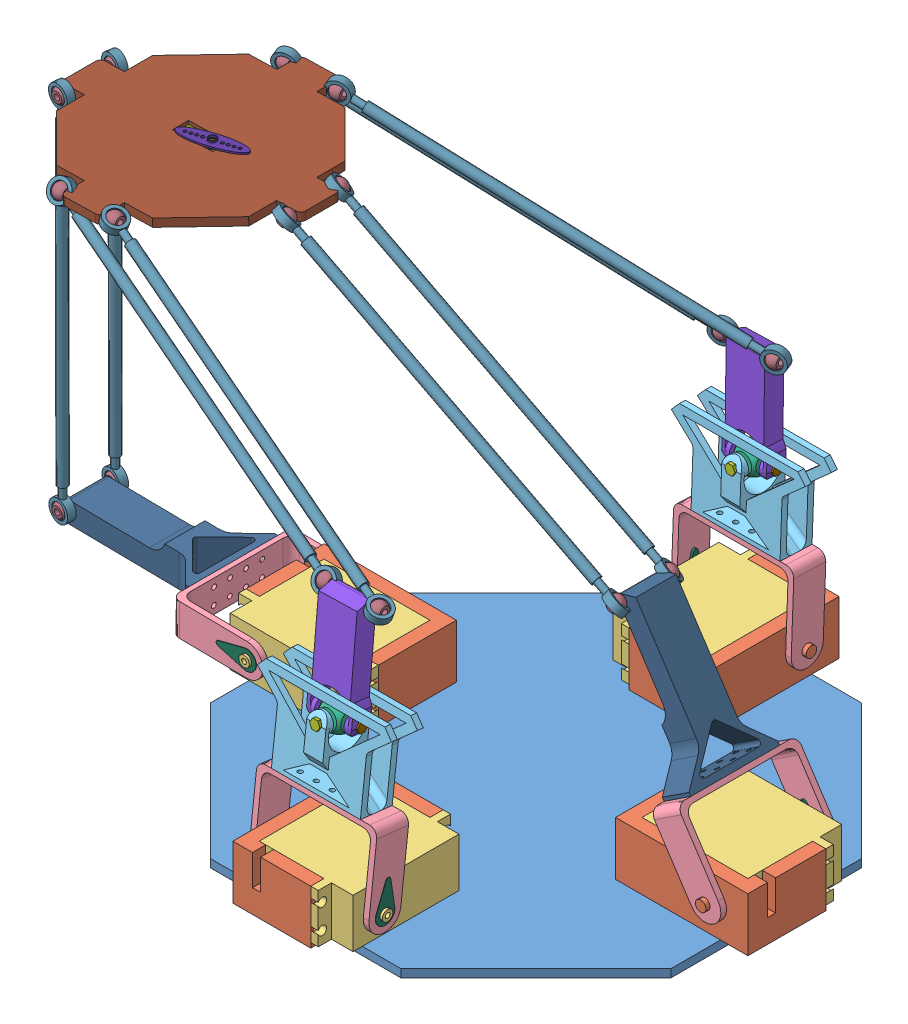
SolidWorks assembly asm(backup), configuration 기본. Lengths in mm.
Overall size (442.11 264.41 321.27).
68 component instances, 17 part files, 159 mates.
Components (placement in the parent):
- delta_base_-1: delta_base_ [기본] at (16.2815 -22.3997 221) size (287.2 5 287.2)
- servobracket1_-1: servobracket1_ [기본] at (8418.954 -14.3997 21660.4366) x (0 0 -1) z (0 1 0) size (82.55 54.75 33.48)
- servobracket1_-2: servobracket1_ [기본] at (-21423.155 -14.3997 8623.6725) x (1 0 0) z (0 1 0) size (82.55 54.75 33.48)
- servobracket1_-3: servobracket1_ [기본] at (-8386.3909 -14.3997 -21218.4366) x (0 0 1) z (0 1 0) size (82.55 54.75 33.48)
- servobracket1_-4: servobracket1_ [기본] at (21455.7181 -14.3997 -8181.6725) x (-1 0 0) z (0 1 0) size (82.55 54.75 33.48)
- servo_drive_HV2060MG-1: servo_drive_HV2060MG [기본] at (-103.0792 0.8403 200.815) x (-1 0 0) z (0 0 1) size (82.55 30.48 64.98)
- servo_drive_HV2060MG-2: servo_drive_HV2060MG [기본] at (36.4665 0.8403 101.6393) x (0 0 -1) z (-1 0 0) size (82.55 30.48 64.98)
- servo_drive_HV2060MG-3: servo_drive_HV2060MG [기본] at (135.6423 0.8403 241.185) x (1 0 0) z (0 0 -1) size (82.55 30.48 64.98)
- servo_drive_HV2060MG-4: servo_drive_HV2060MG [기본] at (-3.9035 0.8403 340.3607) x (0 0 1) z (1 0 0) size (82.55 30.48 64.98)
- servobracket2_-1: servobracket2_ [기본] at (20.8415 47.532 352.9063) x (1 0 0) z (0 -0.114353 -0.99344) size (75 57 20)
- servobracket2_-2: servobracket2_ [기본] at (11.7215 47.8073 81.9563) x (-1 0 0) z (0 0.037506 0.999296) size (75 57 20)
- univ_link1-1: univ_link1 [기본] at (14.8415 69.6769 350.3572) x (0 0.114353 0.99344) z (1 0 0) size (28.84 52.05 83.6)
- univ_link1-2: univ_link1 [기본] at (5.7215 70.0827 81.1203) x (0 0.037506 0.999296) z (1 0 0) size (28.84 52.05 83.6)
- ball-1: ball [기본] at (20.8415 84.5835 348.6413) x (-0.999736 -0.022829 0.002628) z (0 -0.114353 -0.99344) size (24 24 18)
- ball-2: ball [기본] at (11.7215 85.0771 80.5575) x (0.999693 0.024771 -0.00093) z (0 0.037506 0.999296) size (24 24 18)
- univ_bolt_-1: univ_bolt_ [기본] at (20.8415 82.8682 333.7399) x (1 0 0) z (0 -0.99344 0.114353) size (6.46 12 5.59)
- univ_bolt_-2: univ_bolt_ [기본] at (11.7215 85.6397 95.5471) x (0.5 -0.865416 0.032481) z (0.866025 0.499648 -0.018753) size (6.46 12 5.59)
- univ_bolt_-3: univ_bolt_ [기본] at (20.8415 86.2988 363.5431) x (1 0 0) z (0 0.99344 -0.114353) size (6.46 12 5.59)
- univ_bolt_-4: univ_bolt_ [기본] at (11.7215 84.5145 65.5682) x (0.5 0.865416 -0.032481) z (0.866025 -0.499648 0.018753) size (6.46 12 5.59)
- univ_link2-3: univ_link2 [기본] at (11.3614 100.2778 85.9912) x (-0.999693 -0.024771 0.00093) z (0 -0.037506 -0.999296) size (28.56 68.77 12)
- univ_bolt2_-1: univ_bolt2_ [기본] at (26.7282 85.449 80.5435) x (0 0.037506 0.999296) z (0.024788 -0.998989 0.037495) size (6.46 12 5.59)
- univ_bolt2_-2: univ_bolt2_ [기본] at (-3.2626 84.7059 80.5714) x (0 -0.037506 -0.999296) z (0.024788 -0.998989 0.037495) size (6.46 12 5.59)
- univ_link2-4: univ_link2 [기본] at (20.5081 98.7858 340.9669) x (0.999736 0.022829 -0.002628) z (0 0.114353 0.99344) size (28.56 68.77 12)
- univ_bolt2_-3: univ_bolt2_ [기본] at (5.8568 84.2413 348.6807) x (0 -0.114353 -0.99344) z (0.02298 -0.993178 0.114323) size (6.46 12 5.59)
- univ_bolt2_-4: univ_bolt2_ [기본] at (35.8489 84.9262 348.6019) x (0 0.114353 0.99344) z (0.02298 -0.993178 0.114323) size (6.46 12 5.59)
- servobracket2_-3: servobracket2_ [기본] at (-167.995 1.4804 225.56) x (0 0 1) z (0.013619 0.999907 0) size (75 57 20)
- servobracket2_-4: servobracket2_ [기본] at (127.7255 40.1017 216.44) x (0 0 -1) z (-0.835348 -0.549722 0) size (75 57 20)
- link1_-1: link1_ [기본] at (119.372 34.6045 244.19) x (0 0 -1) z (0.549722 -0.835348 0) size (55.5 20 93)
- link1_-2: link1_ [기본] at (-167.8588 11.4795 197.81) x (0 0 1) z (0.999907 -0.013619 0) size (55.5 20 93)
- delta_end_-1: delta_end_ [기본] at (-185.4361 233.7506 228.4598) x (-0.999712 -0.023985 0) z (0 0 1) size (150 5 150)
- link_bridge_-1: link_bridge_ [기본] at (78.2493 115.2848 216.4377) x (-1 0 0) z (0 1 0) size (4.5 28.5 4.5)
- bearing-1: bearing [기본] at (78.2493 115.2848 200.0127) x (0 1 0) z (1 0 0) size (9.35 6.85 9.35)
- link_bridge_-2: link_bridge_ [기본] at (-115.3963 232.9302 228.4598) x (0.013819 0.999905 0) z (0.999905 -0.013819 0) size (4.5 28.5 4.5)
- bearing-2: bearing [기본] at (-115.3963 232.9302 212.0348) x (0.999983 -0.005841 0) z (-0.005841 -0.999983 0) size (9.35 6.85 9.35)
- bearing-3: bearing [기본] at (78.2493 115.2848 232.8627) x (1 0 0) z (0 -1 0) size (9.35 6.85 9.35)
- bearing-4: bearing [기본] at (-115.3963 232.9302 244.8848) x (0 -1 0) z (1 0 0) size (9.35 6.85 9.35)
- rod-1: rod [기본] at (78.2493 115.2848 232.8627) x (-0.371477 -0.533829 -0.759626) z (-0.85344 0.51849 0.052984) size (13.45 6 240.35)
- rod-2: rod [기본] at (-115.3963 232.9302 212.0348) x (0.350098 0.495 0.79524) z (0.85344 -0.51849 -0.052984) size (13.45 6 240.35)
- link_bridge_-3: link_bridge_ [기본] at (-255.356 229.5724 228.4598) x (0.064888 0.997893 0) z (0.997893 -0.064888 0) size (4.5 28.5 4.5)
- bearing-5: bearing [기본] at (-255.356 229.5724 244.8848) x (-0.114329 0.993443 0) z (-0.993443 -0.114329 0) size (9.35 6.85 9.35)
- bearing-6: bearing [기본] at (-255.356 229.5724 212.0348) x (1 0 0) z (0 -1 0) size (9.35 6.85 9.35)
- link_bridge_-4: link_bridge_ [기본] at (-257.9888 2.7062 225.5623) x (1 0 0) z (0 -1 0) size (4.5 28.5 4.5)
- bearing-7: bearing [기본] at (-257.9888 2.7062 209.1373) x (1 0 0) z (0 -1 0) size (9.35 6.85 9.35)
- bearing-8: bearing [기본] at (-257.9888 2.7062 241.9873) x (-1 0 0) z (0 -1 0) size (9.35 6.85 9.35)
- rod-3: rod [기본] at (-255.356 229.5724 212.0348) x (0.986689 -0.01352 0.162053) z (-0.011603 -0.999851 -0.01277) size (13.45 6 240.35)
- rod-4: rod [기본] at (-257.9888 2.7062 241.9873) x (-0.992561 0.013065 -0.121049) z (0.011603 0.999851 0.01277) size (13.45 6 240.35)
- link_bridge_-5: link_bridge_ [기본] at (-185.3762 231.2513 158.4598) x (-0.023985 0.999712 0) z (0 0 1) size (4.5 28.5 4.5)
- link_bridge_-6: link_bridge_ [기본] at (9.7461 144.8824 81.3149) x (-0.024303 0.986812 0.160038) z (-0.004882 0.159966 -0.98711) size (4.5 28.5 4.5)
- bearing-9: bearing [기본] at (-201.7964 230.8574 158.4598) x (0.000254 -0.010595 -0.999944) z (0.023983 -0.999656 0.010598) size (9.35 6.85 9.35)
- bearing-10: bearing [기본] at (-168.9559 231.6453 158.4598) x (-0.020319 0.846909 0.531349) z (0.012744 -0.531196 0.847153) size (9.35 6.85 9.35)
- bearing-11: bearing [기본] at (-6.6739 144.4756 81.3302) x (0.024303 -0.986812 -0.160038) z (0.004882 -0.159966 0.98711) size (9.35 6.85 9.35)
- bearing-12: bearing [기본] at (26.1661 145.2893 81.2997) x (-0.024303 0.986812 0.160038) z (0.004882 -0.159966 0.98711) size (9.35 6.85 9.35)
- rod-5: rod [기본] at (-201.7964 230.8574 158.4598) x (0.388785 0.920131 -0.046957) z (0.85995 -0.380704 -0.339928) size (13.45 6 240.35)
- rod-6: rod [기본] at (26.1661 145.2893 81.2997) x (-0.367193 -0.924119 0.1057) z (-0.859947 0.38059 0.340062) size (13.45 6 240.35)
- link_bridge_-8: link_bridge_ [기본] at (19.9847 143.6099 338.8271) x (-0.022739 0.999274 0.030581) z (0.003324 -0.030514 0.999529) size (4.5 28.5 4.5)
- bearing-13: bearing [기본] at (36.4053 143.9849 338.7839) x (-0.021503 0.969673 0.243459) z (0.008106 -0.243338 0.969908) size (9.35 6.85 9.35)
- bearing-15: bearing [기본] at (3.564 143.2349 338.8702) x (0.022738 -0.999273 -0.030614) z (0.003325 -0.030546 0.999528) size (9.35 6.85 9.35)
- rod-8: rod [기본] at (36.4053 143.9849 338.7839) x (-0.186319 0.015405 0.982368) z (-0.905074 0.386339 -0.177718) size (13.45 6 240.35)
- rod-9: rod [기본] at (3.564 143.2349 338.8702) x (-0.419444 -0.741594 0.523551) z (-0.90507 0.386172 -0.178098) size (13.45 6 240.35)
- servobracket3_-2: servobracket3_ [기본] at (153.5748 0.8403 177.7076) x (-0.835348 -0.549722 0) z (-0.549722 0.835348 0) size (12 5 24.89)
- servobracket3_-3: servobracket3_ [기본] at (54.5739 0.8403 358.2932) x (0 0.114353 0.99344) z (0 0.99344 -0.114353) size (12 5 24.89)
- servobracket3_-4: servobracket3_ [기본] at (-22.0109 0.8403 83.7068) x (0 -0.037506 -0.999296) z (0 0.999296 -0.037506) size (12 5 24.89)
- servobracket3_-5: servobracket3_ [기본] at (-121.0117 0.8403 259.2924) x (-0.013619 -0.999907 0) z (-0.999907 0.013619 0) size (12 5 24.89)
- link_bridge_-9: link_bridge_ [기본] at (-185.3762 231.2513 298.4598) x (-0.023985 0.999712 0) z (0 0 -1) size (4.5 28.5 4.5)
- bearing-17: bearing [기본] at (-168.9559 231.6453 298.4598) x (-0.023288 0.970695 0.239183) z (-0.005737 0.239114 -0.970974) size (9.35 6.85 9.35)
- bearing-18: bearing [기본] at (-201.7964 230.8574 298.4598) x (-0.021793 0.908344 0.417655) z (0.010017 -0.417535 0.908606) size (9.35 6.85 9.35)
- motor-1: motor [기본] at (-185.0284 216.7555 228.4598) x (-0.999712 -0.023985 0) z (-0.023985 0.999712 0) size (32 10 18)
- motor_connect-1: motor_connect [기본] at (-177.9743 235.4301 228.4598) x (0.965622 0.023167 -0.258916) z (0.023985 -0.999712 0) size (38 10 5)
Mates (geometry in assembly coordinates):
- 동심1: concentric anti-aligned: cylinder of delta_base_-1 through (11.2815 -17.3997 82.46) axis (0 -1 0) radius 1.5; cylinder of servobracket1_-1 through (11.2815 -17.3997 82.46) axis (0 1 0) radius 1.5
- 동심2: concentric anti-aligned: cylinder of delta_base_-1 through (21.2815 -17.3997 92.46) axis (0 -1 0) radius 1.5; cylinder of servobracket1_-1 through (21.2815 -17.3997 92.46) axis (0 1 0) radius 1.5
- 일치1: coincident anti-aligned: plane of delta_base_-1 through (16.2815 -17.3997 221) normal (0 1 0); plane of servobracket1_-1 through (8418.954 -17.3997 21660.4366) normal (0 -1 0)
- 동심3: concentric anti-aligned: cylinder of delta_base_-1 through (154.8215 -17.3997 216) axis (0 -1 0) radius 1.5; cylinder of servobracket1_-2 through (154.8215 -17.3997 216) axis (0 1 0) radius 1.5
- 동심4: concentric anti-aligned: cylinder of delta_base_-1 through (144.8215 -17.3997 226) axis (0 -1 0) radius 1.5; cylinder of servobracket1_-2 through (144.8215 -17.3997 226) axis (0 1 0) radius 1.5
- 일치4: coincident anti-aligned: plane of delta_base_-1 through (16.2815 -17.3997 221) normal (0 1 0); plane of servobracket1_-2 through (-21423.155 -17.3997 8623.6725) normal (0 -1 0)
- 동심5: concentric anti-aligned: cylinder of delta_base_-1 through (21.2815 -17.3997 359.54) axis (0 -1 0) radius 1.5; cylinder of servobracket1_-3 through (21.2815 -17.3997 359.54) axis (0 1 0) radius 1.5
- 동심6: concentric anti-aligned: cylinder of delta_base_-1 through (11.2815 -17.3997 349.54) axis (0 -1 0) radius 1.5; cylinder of servobracket1_-3 through (11.2815 -17.3997 349.54) axis (0 1 0) radius 1.5
- 일치5: coincident anti-aligned: plane of delta_base_-1 through (16.2815 -17.3997 221) normal (0 1 0); plane of servobracket1_-3 through (-8386.3909 -17.3997 -21218.4366) normal (0 -1 0)
- 동심7: concentric anti-aligned: cylinder of delta_base_-1 through (-122.2585 -17.3997 226) axis (0 -1 0) radius 1.5; cylinder of servobracket1_-4 through (-122.2585 -17.3997 226) axis (0 1 0) radius 1.5
- 동심8: concentric anti-aligned: cylinder of delta_base_-1 through (-112.2585 -17.3997 216) axis (0 -1 0) radius 1.5; cylinder of servobracket1_-4 through (-112.2585 -17.3997 216) axis (0 1 0) radius 1.5
- 일치6: coincident anti-aligned: plane of delta_base_-1 through (16.2815 -17.3997 221) normal (0 1 0); plane of servobracket1_-4 through (21455.7181 -17.3997 -8181.6725) normal (0 -1 0)
- 일치7: coincident anti-aligned: plane of servobracket1_-4 through (-70.0592 16.0803 241.1804) normal (-1 0 0); plane of servo_drive_HV2060MG-1 through (-70.0592 16.0803 241.1904) normal (1 0 0)
- 일치8: coincident anti-aligned: plane of servobracket1_-4 through (-70.0592 16.0803 200.815) normal (0 0 1); plane of servo_drive_HV2060MG-1 through (-103.0792 0.8403 200.815) normal (0 0 -1)
- 일치9: coincident anti-aligned: plane of servobracket1_-4 through (21455.7181 -14.3997 -8181.6725) normal (0 1 0); plane of servo_drive_HV2060MG-1 through (-136.0992 -14.3997 241.1904) normal (0 -1 0)
- 일치10: coincident anti-aligned: plane of servobracket1_-1 through (-3.8989 16.0803 134.6593) normal (0 0 -1); plane of servo_drive_HV2060MG-2 through (-3.9089 16.0803 134.6593) normal (0 0 1)
- 일치11: coincident anti-aligned: plane of servobracket1_-1 through (36.4665 16.0803 134.6593) normal (-1 0 0); plane of servo_drive_HV2060MG-2 through (36.4665 0.8403 101.6393) normal (1 0 0)
- 일치12: coincident anti-aligned: plane of servobracket1_-1 through (8418.954 -14.3997 21660.4366) normal (0 1 0); plane of servo_drive_HV2060MG-2 through (-3.9089 -14.3997 68.6193) normal (0 -1 0)
- 일치13: coincident anti-aligned: plane of servobracket1_-2 through (102.6223 16.0803 200.8196) normal (1 0 0); plane of servo_drive_HV2060MG-3 through (102.6223 16.0803 200.8096) normal (-1 0 0)
- 일치14: coincident anti-aligned: plane of servobracket1_-2 through (102.6223 16.0803 241.185) normal (0 0 -1); plane of servo_drive_HV2060MG-3 through (135.6423 0.8403 241.185) normal (0 0 1)
- 일치15: coincident anti-aligned: plane of servobracket1_-2 through (-21423.155 -14.3997 8623.6725) normal (0 1 0); plane of servo_drive_HV2060MG-3 through (168.6623 -14.3997 200.8096) normal (0 -1 0)
- 일치16: coincident anti-aligned: plane of servobracket1_-3 through (36.4619 16.0803 307.3407) normal (0 0 1); plane of servo_drive_HV2060MG-4 through (36.4719 16.0803 307.3407) normal (0 0 -1)
- 일치17: coincident anti-aligned: plane of servobracket1_-3 through (-3.9035 16.0803 307.3407) normal (1 0 0); plane of servo_drive_HV2060MG-4 through (-3.9035 0.8403 340.3607) normal (-1 0 0)
- 일치18: coincident anti-aligned: plane of servobracket1_-3 through (-8386.3909 -14.3997 -21218.4366) normal (0 1 0); plane of servo_drive_HV2060MG-4 through (36.4719 -14.3997 373.3807) normal (0 -1 0)
- 동심12: concentric aligned: circle of servobracket1_-3; cylinder of servobracket2_-1 through (-12.1585 0.8403 358.2809) axis (-1 0 0) radius 3.3
- 일치19: coincident anti-aligned: plane of servobracket1_-3 through (-12.1585 16.0803 381.6357) normal (-1 0 0); plane of servobracket2_-1 through (-12.1585 -5.6421 370.8498) normal (1 0 0)
- 동심13: concentric aligned: circle of servobracket1_-1; cylinder of servobracket2_-2 through (44.7215 0.8403 83.7191) axis (1 0 0) radius 3.3
- 일치20: coincident anti-aligned: plane of servobracket1_-1 through (44.7215 16.0803 60.3643) normal (1 0 0); plane of servobracket2_-2 through (44.7215 -10.283 74.9857) normal (-1 0 0)
- 동심14: concentric anti-aligned: cylinder of servobracket2_-1 through (15.8415 45.2276 349.3493) axis (0 0.952569 -0.304322) radius 1.5; cylinder of univ_link1-1 through (15.8415 49.9904 347.8276) axis (0 -0.952569 0.304322) radius 1.5
- 동심15: concentric anti-aligned: cylinder of servobracket2_-1 through (25.8415 42.1844 339.8236) axis (0 0.952569 -0.304322) radius 1.5; cylinder of univ_link1-1 through (25.8415 46.9472 338.302) axis (0 -0.952569 0.304322) radius 1.5
- 일치22: coincident anti-aligned: plane of servobracket2_-1 through (20.8415 45.6111 343.9778) normal (0 0.952569 -0.304322); plane of univ_link1-1 through (-6.9085 48.6543 353.5035) normal (0 -0.952569 0.304322)
- 동심16: concentric anti-aligned: cylinder of servobracket2_-2 through (6.7215 46.1154 83.306) axis (0 0.992835 -0.119496) radius 1.5; cylinder of univ_link1-2 through (6.7215 51.0796 82.7085) axis (0 -0.992835 0.119496) radius 1.5
- 동심17: concentric anti-aligned: cylinder of servobracket2_-2 through (16.7215 44.9204 73.3776) axis (0 0.992835 -0.119496) radius 1.5; cylinder of univ_link1-2 through (16.7215 49.8846 72.7802) axis (0 -0.992835 0.119496) radius 1.5
- 일치23: coincident anti-aligned: plane of servobracket2_-2 through (11.7215 47.5036 78.1028) normal (0 0.992835 -0.119496); plane of univ_link1-2 through (-16.0285 48.6985 88.0312) normal (0 -0.992835 0.119496)
- 일치24: coincident anti-aligned: circle of univ_link1-1; circle of ball-1
- 일치26: coincident anti-aligned: plane of univ_link1-1 through (22.4565 74.5175 321.0958) normal (0 0.952569 -0.304322); plane of univ_bolt_-1 through (19.2265 74.5175 321.0958) normal (0 -0.952569 0.304322)
- 동심18: concentric aligned: cylinder of ball-1 through (20.8415 83.2685 339.2957) axis (0 -0.304322 -0.952569) radius 1.55; cylinder of univ_bolt_-1 through (20.8415 80.2253 329.7702) axis (0 -0.304322 -0.952569) radius 1.55
- 일치27: coincident anti-aligned: plane of univ_link1-1 through (14.8415 62.8888 324.8109) normal (0 -0.304322 -0.952569); plane of univ_bolt_-1 through (20.8415 77.1821 320.2445) normal (0 0.304322 0.952569)
- 일치28: coincident anti-aligned: plane of univ_link1-2 through (10.1065 83.3087 86.8874) normal (0 0.992835 -0.119496); plane of univ_bolt_-2 through (13.3365 83.3087 86.8874) normal (0 -0.992835 0.119496)
- 동심19: concentric aligned: cylinder of ball-2 through (11.7215 83.696 66.6963) axis (0 0.119496 0.992835) radius 1.55; cylinder of univ_bolt_-2 through (11.7215 84.891 76.6248) axis (0 0.119496 0.992835) radius 1.55
- 일치29: coincident anti-aligned: plane of univ_link1-2 through (5.7215 71.1884 88.3462) normal (0 0.119496 0.992835); plane of univ_bolt_-2 through (11.7215 86.0859 86.5532) normal (0 -0.119496 -0.992835)
- 동심20: concentric anti-aligned: cylinder of ball-1 through (20.8415 83.2685 339.2957) axis (0 -0.304322 -0.952569) radius 1.55; cylinder of univ_bolt_-3 through (20.8415 82.0513 335.4857) axis (0 0.304322 0.952569) radius 1.55
- 일치30: coincident anti-aligned: plane of univ_link1-1 through (19.2265 82.4299 345.8626) normal (0 0.952569 -0.304322); plane of univ_bolt_-3 through (22.4565 82.4299 345.8626) normal (0 -0.952569 0.304322)
- 일치31: coincident anti-aligned: plane of univ_link1-1 through (14.8415 70.8011 349.5777) normal (0 0.304322 0.952569); plane of univ_bolt_-3 through (20.8415 85.0945 345.0114) normal (0 -0.304322 -0.952569)
- 일치32: coincident anti-aligned: plane of univ_link1-2 through (13.3365 80.2018 61.0737) normal (0 0.992835 -0.119496); plane of univ_bolt_-4 through (10.1065 80.2018 61.0737) normal (0 -0.992835 0.119496)
- 동심21: concentric anti-aligned: cylinder of ball-2 through (11.7215 83.696 66.6963) axis (0 0.119496 0.992835) radius 1.55; cylinder of univ_bolt_-4 through (11.7215 84.174 70.6678) axis (0 -0.119496 -0.992835) radius 1.55
- 일치33: coincident anti-aligned: plane of univ_link1-2 through (5.7215 68.0815 62.5325) normal (0 -0.119496 -0.992835); plane of univ_bolt_-4 through (11.7215 82.979 60.7395) normal (0 0.119496 0.992835)
- 일치35: coincident aligned: plane of ball-2 through (2.7017 85.7189 71.9925) normal (0 0.119496 0.992835); plane of univ_link2-3 through (26.1311 86.0375 71.9541) normal (0 0.119496 0.992835)
- 일치37: coincident anti-aligned: plane of univ_link2-3 through (24.6929 88.2048 79.2474) normal (0.013811 -0.99274 0.119484); plane of univ_bolt2_-1 through (24.6929 87.6808 74.8938) normal (-0.013811 0.99274 -0.119484)
- 일치38: coincident anti-aligned: plane of ball-2 through (2.7017 85.7189 71.9925) normal (0 0.119496 0.992835); plane of univ_bolt2_-1 through (14.7118 85.8836 71.9727) normal (0 -0.119496 -0.992835)
- 일치39: coincident anti-aligned: plane of ball-2 through (2.7431 83.0992 75.3294) normal (-0.013811 0.99274 -0.119484); plane of univ_bolt2_-1 through (14.7533 82.9054 72.3311) normal (0.013811 -0.99274 0.119484)
- 일치40: coincident anti-aligned: plane of univ_link2-3 through (24.5245 100.3095 77.7905) normal (0.999905 0.013712 -0.00165); plane of univ_bolt2_-1 through (24.7316 84.7109 73.6246) normal (-0.999905 -0.013712 0.00165)
- 일치126: coincident aligned: circle of univ_link1-2; circle of ball-2
- 일치44: coincident anti-aligned: plane of univ_link2-3 through (-1.3046 87.3245 74.9383) normal (0.013811 -0.99274 0.119484); plane of univ_bolt2_-2 through (-1.3046 86.9383 71.7299) normal (-0.013811 0.99274 -0.119484)
- 일치45: coincident anti-aligned: plane of ball-2 through (2.7017 86.0774 74.971) normal (0 -0.119496 -0.992835); plane of univ_bolt2_-2 through (8.7124 86.1598 74.9611) normal (0 0.119496 0.992835)
- 일치46: coincident anti-aligned: plane of ball-2 through (2.7431 83.0992 75.3294) normal (-0.013811 0.99274 -0.119484); plane of univ_bolt2_-2 through (8.7538 83.1816 75.3195) normal (0.013811 -0.99274 0.119484)
- 일치47: coincident anti-aligned: plane of univ_link2-3 through (-1.473 99.9529 77.8334) normal (-0.999905 -0.013712 0.00165); plane of univ_bolt2_-2 through (-1.2659 84.3543 73.6675) normal (0.999905 0.013712 -0.00165)
- 일치49: coincident aligned: plane of ball-1 through (29.8231 83.1254 333.5676) normal (0 -0.304322 -0.952569); plane of univ_link2-4 through (6.4157 82.8577 333.6531) normal (0 -0.304322 -0.952569)
- 일치50: coincident anti-aligned: plane of univ_link2-4 through (7.8205 81.8296 326.1081) normal (0.011887 -0.952502 0.3043); plane of univ_bolt2_-3 through (7.8205 83.1641 330.2851) normal (-0.011887 0.952502 -0.3043)
- 일치51: coincident anti-aligned: plane of ball-1 through (29.8231 83.1254 333.5676) normal (0 -0.304322 -0.952569); plane of univ_bolt2_-3 through (17.8352 82.9896 333.611) normal (0 0.304322 0.952569)
- 일치52: coincident anti-aligned: plane of ball-1 through (29.8587 79.3549 331.6228) normal (-0.011887 0.952502 -0.3043); plane of univ_bolt2_-3 through (17.8709 80.1321 334.5239) normal (0.011887 -0.952502 0.3043)
- 일치53: coincident anti-aligned: plane of univ_link2-4 through (7.6755 93.4437 322.3977) normal (-0.999929 -0.011323 0.003617); plane of univ_bolt2_-3 through (7.8537 80.9912 332.6747) normal (0.999929 0.011323 -0.003617)
- 일치54: coincident anti-aligned: plane of univ_link2-4 through (33.8187 83.458 330.1896) normal (0.011887 -0.952502 0.3043); plane of univ_bolt2_-4 through (33.8187 84.4414 333.2679) normal (-0.011887 0.952502 -0.3043)
- 일치55: coincident anti-aligned: plane of ball-1 through (29.8231 82.2124 330.7099) normal (0 0.304322 0.952569); plane of univ_bolt2_-4 through (23.8348 82.1446 330.7316) normal (0 -0.304322 -0.952569)
- 일치56: coincident anti-aligned: plane of ball-1 through (29.8587 79.3549 331.6228) normal (-0.011887 0.952502 -0.3043); plane of univ_bolt2_-4 through (23.8704 79.2871 331.6445) normal (0.011887 -0.952502 0.3043)
- 일치57: coincident anti-aligned: plane of univ_link2-4 through (33.6737 93.7381 322.3037) normal (0.999929 0.011323 -0.003617); plane of univ_bolt2_-4 through (33.8519 81.2856 332.5807) normal (-0.999929 -0.011323 0.003617)
- 동심22: concentric aligned: circle of servobracket1_-4; cylinder of servobracket2_-3 through (-120.9993 0.8403 192.56) axis (0 0 -1) radius 3.3
- 일치58: coincident anti-aligned: plane of servobracket1_-4 through (-144.3542 16.0803 192.56) normal (0 0 -1); plane of servobracket2_-3 through (-111.1365 -9.2949 192.56) normal (0 0 1)
- 동심23: concentric aligned: circle of servobracket1_-2; cylinder of servobracket2_-4 through (153.5624 0.8403 249.44) axis (0 0 1) radius 3.3
- 일치59: coincident anti-aligned: plane of servobracket1_-2 through (176.9173 16.0803 249.44) normal (0 0 1); plane of servobracket2_-4 through (167.326 -2.4099 249.44) normal (0 0 -1)
- 동심24: concentric anti-aligned: cylinder of servobracket2_-4 through (134.1609 41.7497 221.44) axis (-0.525667 0.85069 0) radius 1.5; cylinder of link1_-1 through (130.4812 47.7046 221.44) axis (0.525667 -0.85069 0) radius 1.5
- 동심25: concentric anti-aligned: cylinder of servobracket2_-4 through (125.6539 36.4931 211.44) axis (-0.525667 0.85069 0) radius 1.5; cylinder of link1_-1 through (121.9743 42.4479 211.44) axis (0.525667 -0.85069 0) radius 1.5
- 일치60: coincident anti-aligned: plane of servobracket2_-4 through (128.8561 40.8228 216.44) normal (-0.525667 0.85069 0); plane of link1_-1 through (137.363 46.0795 188.69) normal (0.525667 -0.85069 0)
- 동심26: concentric anti-aligned: cylinder of servobracket2_-3 through (-166.0633 -3.5463 230.56) axis (-0.999907 0.013619 0) radius 1.5; cylinder of link1_-2 through (-173.0626 -3.451 230.56) axis (0.999907 -0.013619 0) radius 1.5
- 동심27: concentric anti-aligned: cylinder of servobracket2_-3 through (-165.9271 6.4527 220.56) axis (-0.999907 0.013619 0) radius 1.5; cylinder of link1_-2 through (-172.9264 6.5481 220.56) axis (0.999907 -0.013619 0) radius 1.5
- 일치61: coincident anti-aligned: plane of servobracket2_-3 through (-167.995 1.4804 225.56) normal (-0.999907 0.013619 0); plane of link1_-2 through (-168.1312 -8.5186 253.31) normal (0.999907 -0.013619 0)
- 동심29: concentric anti-aligned: cylinder of link1_-1 through (81.5449 117.3868 188.69) axis (0 0 1) radius 2.15; cylinder of link_bridge_-1 through (81.5449 117.3868 228.9377) axis (0 0 -1) radius 2
- 일치66: coincident anti-aligned: plane of link1_-1 through (90.0529 122.6416 228.9377) normal (0 0 1); plane of link_bridge_-1 through (81.5449 117.3868 228.9377) normal (0 0 -1)
- 일치68: coincident anti-aligned: plane of link_bridge_-1 through (81.5449 117.3868 203.4377) normal (0 0 -1); plane of bearing-1 through (81.5449 117.3868 203.4377) normal (0 0 1)
- 동심30: concentric aligned: cylinder of link_bridge_-1 through (81.5449 117.3868 202.1877) axis (0 0 1) radius 1.775; cylinder of bearing-1 through (81.5449 117.3868 196.5877) axis (0 0 1) radius 1.775
- 동심31: concentric anti-aligned: cylinder of delta_end_-1 through (-114.7842 231.1336 141.8271) axis (0 0 1) radius 2; cylinder of link_bridge_-2 through (-114.7842 231.1336 229.3271) axis (0 0 -1) radius 2
- 일치70: coincident anti-aligned: plane of delta_end_-1 through (-184.7482 227.7746 229.3271) normal (0 0 1); plane of link_bridge_-2 through (-114.7842 231.1336 229.3271) normal (0 0 -1)
- 동심32: concentric aligned: cylinder of link_bridge_-2 through (-114.7842 231.1336 202.5771) axis (0 0 1) radius 1.775; cylinder of bearing-2 through (-114.7842 231.1336 196.9771) axis (0 0 1) radius 1.775
- 일치71: coincident anti-aligned: plane of link_bridge_-2 through (-114.7842 231.1336 203.8271) normal (0 0 -1); plane of bearing-2 through (-114.7842 231.1336 203.8271) normal (0 0 1)
- 동심35: concentric anti-aligned: cylinder of link_bridge_-1 through (81.5449 117.3868 230.6877) axis (0 0 -1) radius 1.775; cylinder of bearing-3 through (81.5449 117.3868 229.4377) axis (0 0 1) radius 1.775
- 일치76: coincident anti-aligned: plane of link_bridge_-1 through (81.5449 117.3868 229.4377) normal (0 0 1); plane of bearing-3 through (81.5449 117.3868 229.4377) normal (0 0 -1)
- 일치78: coincident anti-aligned: plane of link_bridge_-2 through (-114.7842 231.1336 229.8271) normal (0 0 1); plane of bearing-4 through (-114.7842 231.1336 229.8271) normal (0 0 -1)
- 동심36: concentric aligned: cylinder of link_bridge_-2 through (-114.7842 231.1336 231.0771) axis (0 0 -1) radius 1.775; cylinder of bearing-4 through (-114.7842 231.1336 236.6771) axis (0 0 -1) radius 1.775
- 일치79: coincident: sphere of bearing-3; circle of rod-1
- 일치80: coincident: sphere of bearing-4; circle of rod-1
- 일치81: coincident: sphere of bearing-1; circle of rod-2
- 일치82: coincident: sphere of bearing-2; circle of rod-2
- 동심37: concentric anti-aligned: cylinder of delta_end_-1 through (-254.7737 229.4152 141.8271) axis (0 0 1) radius 2; cylinder of link_bridge_-3 through (-254.7737 229.4152 229.3271) axis (0 0 -1) radius 2
- 일치83: coincident anti-aligned: plane of delta_end_-1 through (-184.7482 227.7746 204.3271) normal (0 0 -1); plane of link_bridge_-3 through (-254.7737 229.4152 204.3271) normal (0 0 1)
- 동심38: concentric aligned: cylinder of link_bridge_-3 through (-254.7737 229.4152 231.0771) axis (0 0 -1) radius 1.775; cylinder of bearing-5 through (-254.7737 229.4152 236.6771) axis (0 0 -1) radius 1.775
- 일치84: coincident anti-aligned: plane of link_bridge_-3 through (-254.7737 229.4152 229.8271) normal (0 0 1); plane of bearing-5 through (-254.7737 229.4152 229.8271) normal (0 0 -1)
- 동심39: concentric aligned: cylinder of link_bridge_-3 through (-254.7737 229.4152 202.5771) axis (0 0 1) radius 1.775; cylinder of bearing-6 through (-254.7737 229.4152 196.9771) axis (0 0 1) radius 1.775
- 일치85: coincident anti-aligned: plane of link_bridge_-3 through (-254.7737 229.4152 203.8271) normal (0 0 -1); plane of bearing-6 through (-254.7737 229.4152 203.8271) normal (0 0 1)
- 동심40: concentric aligned: cylinder of link1_-2 through (-257.9888 2.7062 253.31) axis (0 0 -1) radius 2.15; cylinder of link_bridge_-4 through (-257.9888 2.7062 238.0623) axis (0 0 -1) radius 2
- 일치86: coincident anti-aligned: plane of link1_-2 through (-258.1228 -7.2929 213.0623) normal (0 0 -1); plane of link_bridge_-4 through (-257.9888 2.7062 213.0623) normal (0 0 1)
- 동심41: concentric aligned: cylinder of link_bridge_-4 through (-257.9888 2.7062 211.3123) axis (0 0 1) radius 1.775; cylinder of bearing-7 through (-257.9888 2.7062 205.7123) axis (0 0 1) radius 1.775
- 일치87: coincident anti-aligned: plane of link_bridge_-4 through (-257.9888 2.7062 212.5623) normal (0 0 -1); plane of bearing-7 through (-257.9888 2.7062 212.5623) normal (0 0 1)
- 동심42: concentric aligned: cylinder of link_bridge_-4 through (-257.9888 2.7062 239.8123) axis (0 0 -1) radius 1.775; cylinder of bearing-8 through (-257.9888 2.7062 245.4123) axis (0 0 -1) radius 1.775
- 일치88: coincident anti-aligned: plane of link_bridge_-4 through (-257.9888 2.7062 238.5623) normal (0 0 1); plane of bearing-8 through (-257.9888 2.7062 238.5623) normal (0 0 -1)
- 일치89: coincident: sphere of bearing-7; circle of rod-3
- 일치91: coincident: sphere of bearing-6; circle of rod-3
- 일치93: coincident: sphere of bearing-5; circle of rod-4
- 일치95: coincident: sphere of bearing-8; circle of rod-4
- 동심43: concentric aligned: cylinder of delta_end_-1 through (-259.7733 229.3538 146.8271) axis (0.999925 0.012275 0) radius 2; cylinder of link_bridge_-5 through (-197.278 230.121 146.8271) axis (0.999925 0.012275 0) radius 2
- 일치96: coincident anti-aligned: plane of delta_end_-1 through (-172.2492 227.928 216.8271) normal (0.999925 0.012275 0); plane of link_bridge_-5 through (-172.2799 230.4278 146.8271) normal (-0.999925 -0.012275 0)
- 동심44: concentric aligned: cylinder of univ_link2-3 through (25.3263 144.4203 69.4598) axis (-0.999905 -0.013712 0.00165) radius 2; cylinder of link_bridge_-6 through (22.9008 144.3871 69.4638) axis (-0.999905 -0.013712 0.00165) radius 2
- 일치97: coincident anti-aligned: plane of univ_link2-3 through (22.9008 143.3116 60.5283) normal (0.999905 0.013712 -0.00165); plane of link_bridge_-6 through (22.9008 144.3871 69.4638) normal (-0.999905 -0.013712 0.00165)
- 동심45: concentric aligned: cylinder of link_bridge_-5 through (-199.0279 230.0995 146.8271) axis (0.999925 0.012275 0) radius 1.775; cylinder of bearing-9 through (-204.6274 230.0308 146.8271) axis (0.999925 0.012275 0) radius 1.775
- 일치98: coincident anti-aligned: plane of link_bridge_-5 through (-197.778 230.1148 146.8271) normal (-0.999925 -0.012275 0); plane of bearing-9 through (-197.778 230.1148 146.8271) normal (0.999925 0.012275 0)
- 동심46: concentric aligned: cylinder of link_bridge_-5 through (-170.53 230.4493 146.8271) axis (-0.999925 -0.012275 0) radius 1.775; cylinder of bearing-10 through (-164.9304 230.5181 146.8271) axis (-0.999925 -0.012275 0) radius 1.775
- 일치99: coincident anti-aligned: plane of link_bridge_-5 through (-171.7799 230.434 146.8271) normal (0.999925 0.012275 0); plane of bearing-10 through (-171.7799 230.434 146.8271) normal (-0.999925 -0.012275 0)
- 동심47: concentric aligned: cylinder of link_bridge_-6 through (-3.8466 144.0203 69.5079) axis (0.999905 0.013712 -0.00165) radius 1.775; cylinder of bearing-11 through (-9.4461 143.9435 69.5172) axis (0.999905 0.013712 -0.00165) radius 1.775
- 일치100: coincident anti-aligned: plane of link_bridge_-6 through (-2.5967 144.0374 69.5059) normal (-0.999905 -0.013712 0.00165); plane of bearing-11 through (-2.5967 144.0374 69.5059) normal (0.999905 0.013712 -0.00165)
- 동심48: concentric aligned: cylinder of link_bridge_-6 through (24.6507 144.4111 69.4609) axis (-0.999905 -0.013712 0.00165) radius 1.775; cylinder of bearing-12 through (30.2501 144.4879 69.4517) axis (-0.999905 -0.013712 0.00165) radius 1.775
- 일치101: coincident anti-aligned: plane of link_bridge_-6 through (23.4008 144.3939 69.463) normal (0.999905 0.013712 -0.00165); plane of bearing-12 through (23.4008 144.3939 69.463) normal (-0.999905 -0.013712 0.00165)
- 일치102: coincident: sphere of bearing-11; circle of rod-5
- 일치103: coincident: sphere of bearing-9; circle of rod-5
- 일치104: coincident: sphere of bearing-12; circle of rod-6
- 일치107: coincident: sphere of bearing-10; circle of rod-6
- 동심50: concentric aligned: cylinder of univ_link2-4 through (5.7231 136.9888 311.6355) axis (0.999929 0.011323 -0.003617) radius 2; cylinder of link_bridge_-8 through (8.1486 137.0163 311.6268) axis (0.999929 0.011323 -0.003617) radius 2
- 일치111: coincident anti-aligned: plane of univ_link2-4 through (8.1486 139.7552 320.1999) normal (-0.999929 -0.011323 0.003617); plane of link_bridge_-8 through (8.1486 137.0163 311.6268) normal (0.999929 0.011323 -0.003617)
- 동심51: concentric aligned: cylinder of link_bridge_-8 through (34.8967 137.3192 311.53) axis (-0.999929 -0.011323 0.003617) radius 1.775; cylinder of bearing-13 through (40.4964 137.3826 311.5097) axis (-0.999929 -0.011323 0.003617) radius 1.775
- 일치112: coincident anti-aligned: plane of link_bridge_-8 through (33.6468 137.305 311.5345) normal (0.999929 0.011323 -0.003617); plane of bearing-13 through (33.6468 137.305 311.5345) normal (-0.999929 -0.011323 0.003617)
- 동심53: concentric aligned: cylinder of link_bridge_-8 through (6.3988 136.9964 311.6331) axis (0.999929 0.011323 -0.003617) radius 1.775; cylinder of bearing-15 through (0.7992 136.933 311.6534) axis (0.999929 0.011323 -0.003617) radius 1.775
- 일치116: coincident anti-aligned: plane of link_bridge_-8 through (7.6487 137.0106 311.6286) normal (-0.999929 -0.011323 0.003617); plane of bearing-15 through (7.6487 137.0106 311.6286) normal (0.999929 0.011323 -0.003617)
- 일치117: coincident: sphere of bearing-13; circle of rod-8
- 일치120: coincident: sphere of bearing-15; circle of rod-9
- 탄젠트2: tangent: circle of ball-1; plane of univ_link2-4 through (11.6353 79.4012 339.4815) normal (0.999929 0.011323 -0.003617)
- 동심56: concentric anti-aligned: cylinder of servo_drive_HV2060MG-3 through (153.5748 0.8403 176.2076) axis (0 0 1) radius 3.302; cylinder of servobracket3_-2 through (153.5748 0.8403 182.7076) axis (0 0 -1) radius 3.3
- 일치123: coincident anti-aligned: plane of servo_drive_HV2060MG-3 through (135.6423 0.8403 182.7076) normal (0 0 -1); plane of servobracket3_-2 through (153.5748 0.8403 182.7076) normal (0 0 1)
- 평행1: parallel anti-aligned: plane of servobracket2_-4 through (124.6294 36.3355 181.44) normal (-0.685651 -0.72793 0); plane of servobracket3_-2 through (157.6887 5.2079 182.7076) normal (0.685651 0.72793 0)
- 동심57: concentric aligned: cylinder of servo_drive_HV2060MG-4 through (61.0739 0.8403 358.2932) axis (-1 0 0) radius 3.302; cylinder of servobracket3_-3 through (59.5739 0.8403 358.2932) axis (-1 0 0) radius 3.3
- 일치127: coincident anti-aligned: plane of servo_drive_HV2060MG-4 through (54.5739 0.8403 340.3607) normal (1 0 0); plane of servobracket3_-3 through (54.5739 0.8403 358.2932) normal (-1 0 0)
- 평행2: parallel anti-aligned: plane of servobracket2_-1 through (55.8415 42.2792 338.7913) normal (0 -0.540495 -0.841347); plane of servobracket3_-3 through (59.5739 4.0833 363.3413) normal (0 0.540495 0.841347)
- 동심58: concentric aligned: cylinder of servo_drive_HV2060MG-2 through (-28.5109 0.8403 83.7068) axis (1 0 0) radius 3.302; cylinder of servobracket3_-4 through (-27.0109 0.8403 83.7068) axis (1 0 0) radius 3.3
- 일치129: coincident anti-aligned: plane of servo_drive_HV2060MG-2 through (-22.0109 0.8403 101.6393) normal (-1 0 0); plane of servobracket3_-4 through (-22.0109 0.8403 83.7068) normal (1 0 0)
- 평행3: parallel anti-aligned: plane of servobracket2_-2 through (-23.2785 46.6311 84.2053) normal (0 -0.141541 0.989932); plane of servobracket3_-4 through (-27.0109 1.6896 77.7672) normal (0 0.141541 -0.989932)
- 동심59: concentric aligned: cylinder of servo_drive_HV2060MG-1 through (-121.0117 0.8403 265.7924) axis (0 0 -1) radius 3.302; cylinder of servobracket3_-5 through (-121.0117 0.8403 264.2924) axis (0 0 -1) radius 3.3
- 일치131: coincident anti-aligned: plane of servo_drive_HV2060MG-1 through (-103.0792 0.8403 259.2924) normal (0 0 1); plane of servobracket3_-5 through (-121.0117 0.8403 259.2924) normal (0 0 -1)
- 평행4: parallel anti-aligned: plane of servobracket2_-3 through (-166.3186 7.4126 260.56) normal (0.27195 0.962311 0); plane of servobracket3_-5 through (-122.6434 -4.9335 264.2924) normal (-0.27195 -0.962311 0)
- 동심60: concentric anti-aligned: cylinder of delta_end_-1 through (-259.7733 229.3538 286.8271) axis (0.999925 0.012275 0) radius 2; cylinder of link_bridge_-9 through (-172.2799 230.4278 286.8271) axis (-0.999925 -0.012275 0) radius 2
- 일치132: coincident anti-aligned: plane of delta_end_-1 through (-197.2473 227.6212 216.8271) normal (-0.999925 -0.012275 0); plane of link_bridge_-9 through (-197.278 230.121 286.8271) normal (0.999925 0.012275 0)
- 동심61: concentric anti-aligned: cylinder of link_bridge_-9 through (-170.53 230.4493 286.8271) axis (-0.999925 -0.012275 0) radius 1.775; cylinder of bearing-17 through (-171.7799 230.434 286.8271) axis (0.999925 0.012275 0) radius 1.775
- 일치133: coincident anti-aligned: plane of link_bridge_-9 through (-171.7799 230.434 286.8271) normal (0.999925 0.012275 0); plane of bearing-17 through (-171.7799 230.434 286.8271) normal (-0.999925 -0.012275 0)
- 동심62: concentric anti-aligned: cylinder of link_bridge_-9 through (-199.0279 230.0995 286.8271) axis (0.999925 0.012275 0) radius 1.775; cylinder of bearing-18 through (-197.778 230.1148 286.8271) axis (-0.999925 -0.012275 0) radius 1.775
- 일치134: coincident anti-aligned: plane of link_bridge_-9 through (-197.778 230.1148 286.8271) normal (-0.999925 -0.012275 0); plane of bearing-18 through (-197.778 230.1148 286.8271) normal (0.999925 0.012275 0)
- 일치136: coincident: circle of rod-8; sphere of bearing-17
- 일치137: coincident: circle of rod-9; sphere of bearing-18
- 탄젠트5: tangent: circle of ball-2; plane of univ_link2-3 through (2.5226 80.0843 68.1382) normal (0.999905 0.013712 -0.00165)
- 일치138: coincident: plane of delta_end_-1 through (-184.7482 227.7746 211.8271) normal (0 0 1); plane of motor-1 through (-172.286 230.9278 211.8271) normal (0 0 -1)
- 일치139: coincident: plane of delta_end_-1 through (-184.7482 227.7746 216.8271) normal (0.012275 -0.999925 0); plane of motor-1 through (-200.747 227.5782 211.8271) normal (-0.012275 0.999925 0)
- 일치140: coincident anti-aligned: plane of delta_end_-1 through (-172.2492 227.928 216.8271) normal (-0.999925 -0.012275 0); plane of motor-1 through (-172.286 230.9278 221.8271) normal (0.999925 0.012275 0)
- 동심63: concentric: cylinder of motor-1 through (-177.9623 234.9302 228.4598) axis (0.023985 -0.999712 0) radius 2; cylinder of motor_connect-1 through (-179.5098 299.4322 228.4598) axis (0.023985 -0.999712 0) radius 2
- 일치141: coincident anti-aligned: plane of motor-1 through (-177.9503 234.4303 228.4598) normal (-0.023985 0.999712 0); plane of motor_connect-1 through (-177.9503 234.4303 228.4598) normal (0.023985 -0.999712 0)
